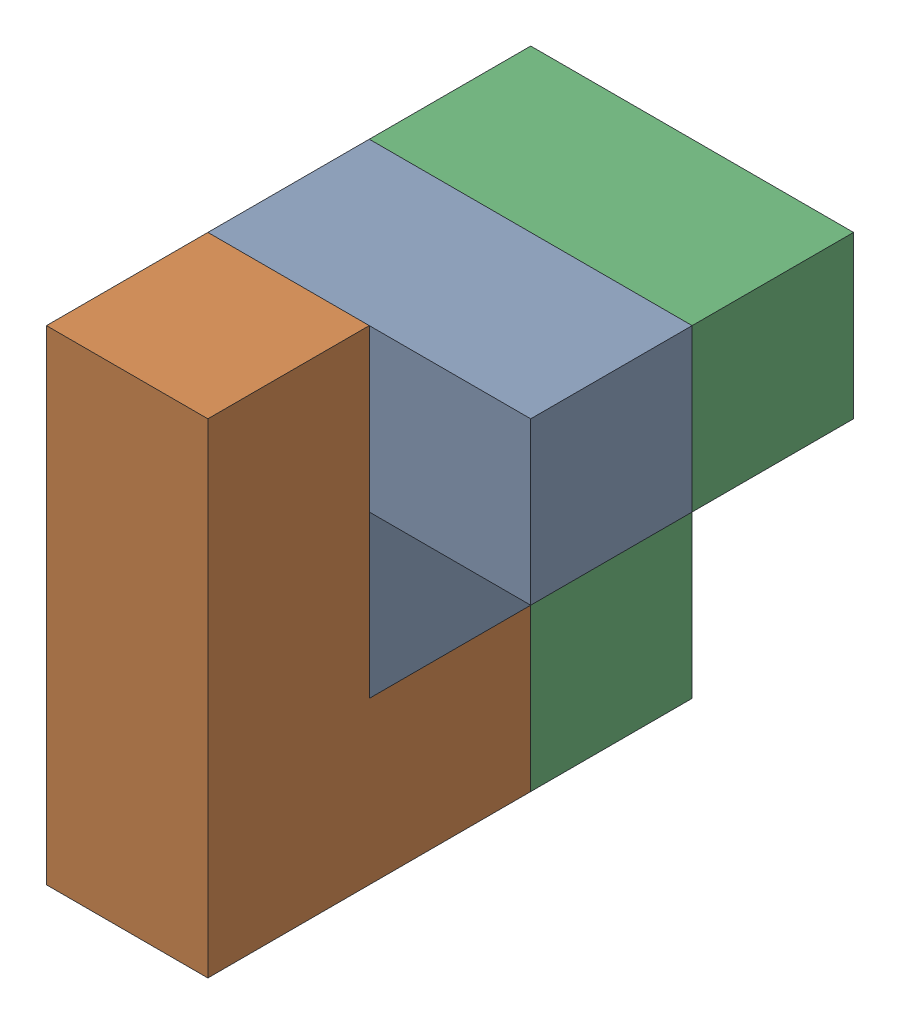
SolidWorks assembly Assem2, configuration Default. Lengths in mm.
Overall size (90 90 90).
3 component instances, 2 part files, 2 mates.
Components (placement in the parent):
- task2part4-2: task2part4 [Default] at (37.8527 -15.2196 -17.0642) size (90 60 30)
- task2Part1-2: task2Part1 [Default] at (97.8527 -45.2196 42.9358) x (0 1 0) z (-1 0 0) size (90 60 30)
- task2Part1-5: task2Part1 [Default] at (67.8527 44.7804 -47.0642) x (0 -1 0) z (0 0 1) size (90 60 30)
Mates (geometry in assembly coordinates):
- Coincident35: coincident: point of task2part4-2; point of task2Part1-2
- Coincident36: coincident: point of task2part4-2; point of task2Part1-5
